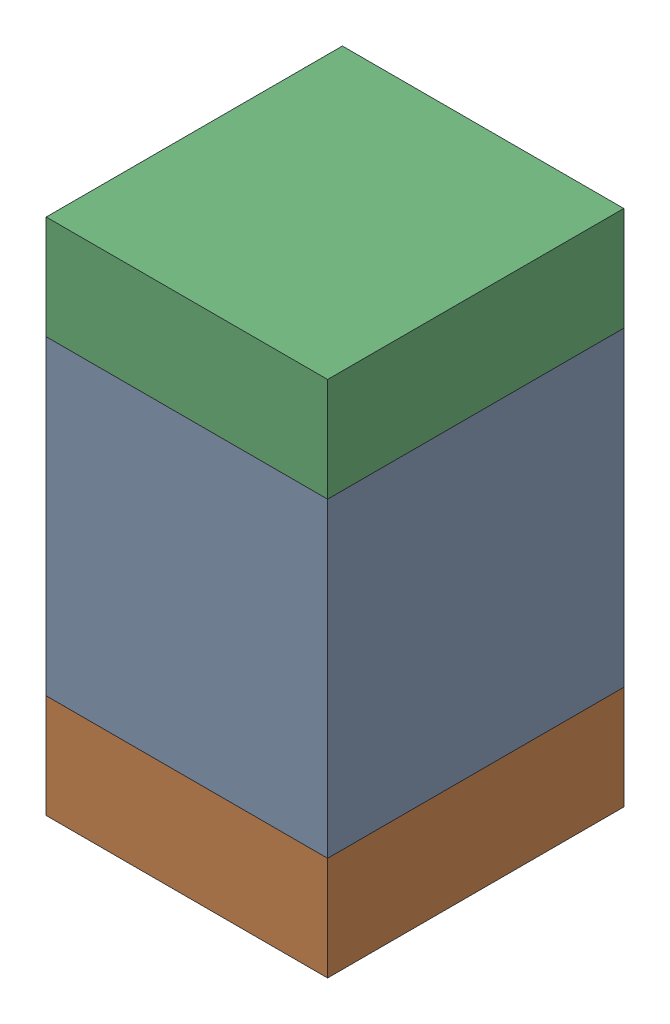
SolidWorks assembly C319_2PCB, configuration Default. Lengths in mm.
Overall size (0.95 1.75 1).
6 component instances, 2 part files, 0 mates.
Components (placement in the parent):
- 761616384-1: 761616384 [Default] at (126.6 96.9 0) size (0.95 1.05 1)
  - Extruded_5-1: Extruded_5 [Default] at origin size (0.95 1.05 1)
- 761616520-1: 761616520 [Default] at (126.6 96.2 0) size (0.95 0.35 1)
  - Extruded_6-1: Extruded_6 [Default] at origin size (0.95 0.35 1)
- 761616520-2: 761616520 [Default] at (126.6 97.6 0) size (0.95 0.35 1)
  - Extruded_6-1: Extruded_6 [Default] at origin size (0.95 0.35 1)
